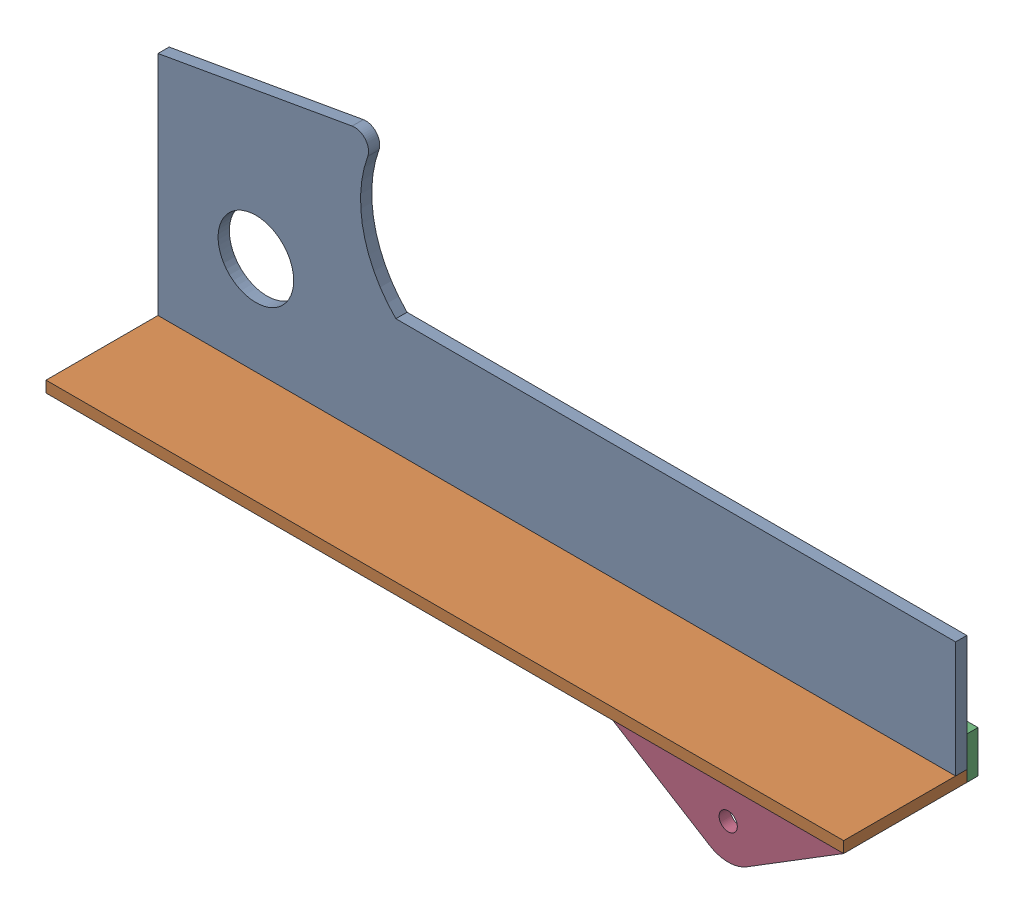
SolidWorks assembly ТП.016.03.05.00 - Ложемент, configuration Правый. Lengths in mm.
Overall size (285 120.68 48).
4 component instances, 4 part files, 12 mates.
Components (placement in the parent):
- ТП.016.03.05.01 - Ложемент бок (4мм)-1: ТП.016.03.05.01 - Ложемент бок (4мм) [--] at origin size (285 93.38 4)
- ТП.016.03.05.02 - Ложемент низ (4мм)-1: ТП.016.03.05.02 - Ложемент низ (4мм) [--] at (250 -35 -4) size (285 4 44)
- ТП.016.03.05.03 - Хомут связки (4мм)-1: ТП.016.03.05.03 - Хомут связки (4мм) [--] at (250 -39 -4) size (82.5 38.3 4)
- ТП.016.03.05.04 - Шайба связки (4мм)-1: ТП.016.03.05.04 - Шайба связки (4мм) [--] at (250 -39 40) size (82.5 23.3 4)
Mates (geometry in assembly coordinates):
- Совпадение1: coincident: plane of ТП.016.03.05.01 - Ложемент бок (4мм)-1 through (0 -35 -4) normal (0 -1 0); plane of ТП.016.03.05.02 - Ложемент низ (4мм)-1 through (250 -35 -4) normal (0 1 0)
- Совпадение2: coincident: plane of ТП.016.03.05.01 - Ложемент бок (4мм)-1 through (250 -35 -4) normal (1 0 0); plane of ТП.016.03.05.02 - Ложемент низ (4мм)-1 through (250 -39 40) normal (1 0 0)
- Совпадение3: coincident: plane of ТП.016.03.05.01 - Ложемент бок (4мм)-1 through (80.67 37.0346 -4) normal (0 0 -1); plane of ТП.016.03.05.02 - Ложемент низ (4мм)-1 through (-35 -39 -4) normal (0 0 -1)
- Совпадение4: coincident: plane of ТП.016.03.05.01 - Ложемент бок (4мм)-1 through (75.3946 35.3104 0) normal (0 0 1); plane of ТП.016.03.05.02 - Ложемент низ (4мм)-1 through (-35 -39 0) normal (0 0 1)
- Совпадение5: coincident: plane of ТП.016.03.05.01 - Ложемент бок (4мм)-1 through (80.67 37.0346 -4) normal (0 0 -1); plane of ТП.016.03.05.03 - Хомут связки (4мм)-1 through (208.7492 -49.65 -4) normal (0 0 1)
- Совпадение6: coincident: plane of ТП.016.03.05.01 - Ложемент бок (4мм)-1 through (250 -35 -4) normal (1 0 0); plane of ТП.016.03.05.03 - Хомут связки (4мм)-1 through (250 -24 -8) normal (1 0 0)
- Совпадение7: coincident: line of ТП.016.03.05.02 - Ложемент низ (4мм)-1 through (250 -39 40) axis (0 0 -1); line of ТП.016.03.05.03 - Хомут связки (4мм)-1 through (250 -39 -8) axis (0 0 1)
- Совпадение8: coincident: plane of ТП.016.03.05.01 - Ложемент бок (4мм)-1 through (75.3946 35.3104 0) normal (0 0 1); plane of ТП.016.03.05.03 - Хомут связки (4мм)-1 through (208.7492 -49.65 0) normal (0 0 -1)
- Совпадение9: coincident: plane of ТП.016.03.05.02 - Ложемент низ (4мм)-1 through (250 -39 -4) normal (0 -1 0); plane of ТП.016.03.05.04 - Шайба связки (4мм)-1 through (167.4983 -39 36) normal (0 1 0)
- Совпадение10: coincident: plane of ТП.016.03.05.02 - Ложемент низ (4мм)-1 through (-35 -39 40) normal (0 0 1); plane of ТП.016.03.05.04 - Шайба связки (4мм)-1 through (208.7492 -49.65 40) normal (0 0 1)
- Совпадение11: coincident: line of ТП.016.03.05.02 - Ложемент низ (4мм)-1 through (250 -39 40) axis (0 0 -1); line of ТП.016.03.05.04 - Шайба связки (4мм)-1 through (250 -39 36) axis (0 0 1)
- Совпадение12: coincident: plane of ТП.016.03.05.02 - Ложемент низ (4мм)-1 through (-35 -39 -4) normal (0 0 -1); plane of ТП.016.03.05.04 - Шайба связки (4мм)-1 through (208.7492 -49.65 -44) normal (0 0 -1)
